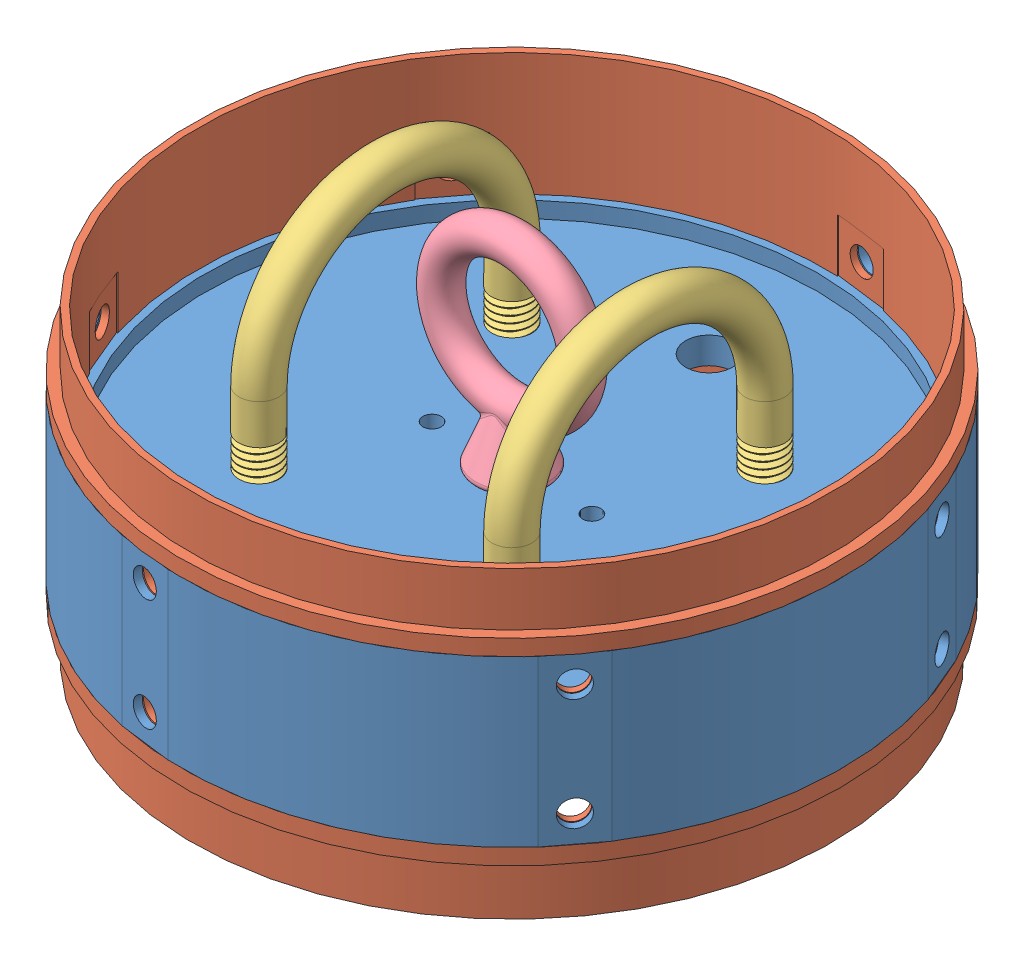
SolidWorks assembly Recovery Bulkhead Assembly, configuration Default. Lengths in mm.
Overall size (221.56 91.29 221.56).
6 component instances, 4 part files, 12 mates.
Components (placement in the parent):
- Recovery Bulkhead Main Part-1: Recovery Bulkhead Main Part [Default] at origin size (157.18 39.37 157.18)
- Recovery Bulkhead Connector-1: Recovery Bulkhead Connector [Default] at (0 6.985 0) x (0.907673 0 0.419679) z (-0.419679 0 0.907673) size (157.18 29.21 157.18)
- Recovery Bulkhead Connector-2: Recovery Bulkhead Connector [Default] at (0 -6.985 0) x (-0.648044 0 -0.761603) z (-0.761603 0 0.648044) size (157.18 29.21 157.18)
- 8896T810_304 SS U-BOLT-1: 8896T810_304 SS U-BOLT [8896T81] at (-30.1625 20.1745 0) x (0 0 1) z (1 0 0) size (82.55 76.73 25.4)
- 8896T810_304 SS U-BOLT-2: 8896T810_304 SS U-BOLT [8896T81] at (30.1625 20.1745 0) x (0 0 1) z (1 0 0) size (82.55 76.73 25.4)
- 33045T810_304 STAINLESS STEEL EYEBOLT-2: 33045T810_304 STAINLESS STEEL EYEBOLT [33045T81] at (0 32.9406 0) size (42.07 83.17 17.46)
Mates (geometry in assembly coordinates):
- Concentric1: concentric aligned: cylinder of Recovery Bulkhead Main Part-1 through (0 19.685 0) axis (0 -1 0) radius 76.454; cylinder of Recovery Bulkhead Connector-1 through (0 -48.015 0) axis (0 -1 0) radius 76.2
- Concentric2: concentric aligned: cylinder of Recovery Bulkhead Main Part-1 through (-72.4523 13.335 30.4412) axis (-0.921931 0 0.387354) radius 3.175; cylinder of Recovery Bulkhead Connector-1 through (-70.2511 13.335 29.5164) axis (-0.921931 0 0.387354) radius 3.175
- Concentric3: concentric aligned: cylinder of Recovery Bulkhead Main Part-1 through (0 -19.685 0) axis (0 1 0) radius 76.454; cylinder of Recovery Bulkhead Connector-2 through (0 48.015 0) axis (0 1 0) radius 76.2
- Concentric4: concentric aligned: cylinder of Recovery Bulkhead Main Part-1 through (-72.4523 -13.335 30.4412) axis (-0.921931 0 0.387354) radius 3.175; cylinder of Recovery Bulkhead Connector-2 through (-70.2511 -13.335 29.5164) axis (-0.921931 0 0.387354) radius 3.175
- Coincident1: coincident anti-aligned: plane of Recovery Bulkhead Main Part-1 through (0 -3.175 0) normal (0 -1 0); plane of 8896T810_304 SS U-BOLT-2 through (17.4625 -3.175 -41.275) normal (0 1 0)
- Coincident2: coincident anti-aligned: plane of Recovery Bulkhead Main Part-1 through (0 -3.175 0) normal (0 -1 0); plane of 8896T810_304 SS U-BOLT-1 through (-42.8625 -3.175 -41.275) normal (0 1 0)
- Concentric5: concentric anti-aligned: cylinder of Recovery Bulkhead Main Part-1 through (-30.1625 3.175 -30.1625) axis (0 1 0) radius 4.7625; cylinder of 8896T810_304 SS U-BOLT-1 through (-30.1625 10.6495 -30.1625) axis (0 -1 0) radius 4.7625
- Concentric6: concentric anti-aligned: cylinder of Recovery Bulkhead Main Part-1 through (-30.1625 3.175 30.1625) axis (0 1 0) radius 4.7625; cylinder of 8896T810_304 SS U-BOLT-1 through (-30.1625 20.1745 30.1625) axis (0 -1 0) radius 4.7625
- Concentric7: concentric anti-aligned: cylinder of Recovery Bulkhead Main Part-1 through (30.1625 3.175 -30.1625) axis (0 1 0) radius 4.7625; cylinder of 8896T810_304 SS U-BOLT-2 through (30.1625 10.6495 -30.1625) axis (0 -1 0) radius 4.7625
- Concentric8: concentric anti-aligned: cylinder of Recovery Bulkhead Main Part-1 through (30.1625 3.175 30.1625) axis (0 1 0) radius 4.7625; cylinder of 8896T810_304 SS U-BOLT-2 through (30.1625 20.1745 30.1625) axis (0 -1 0) radius 4.7625
- Concentric11: concentric anti-aligned: cylinder of Recovery Bulkhead Main Part-1 through (0 3.175 0) axis (0 1 0) radius 4.7625; circle of 33045T810_304 STAINLESS STEEL EYEBOLT-2
- Coincident4: coincident anti-aligned: plane of Recovery Bulkhead Main Part-1 through (0 3.175 0) normal (0 1 0); plane of 33045T810_304 STAINLESS STEEL EYEBOLT-2 through (0 3.175 0) normal (0 -1 0)
